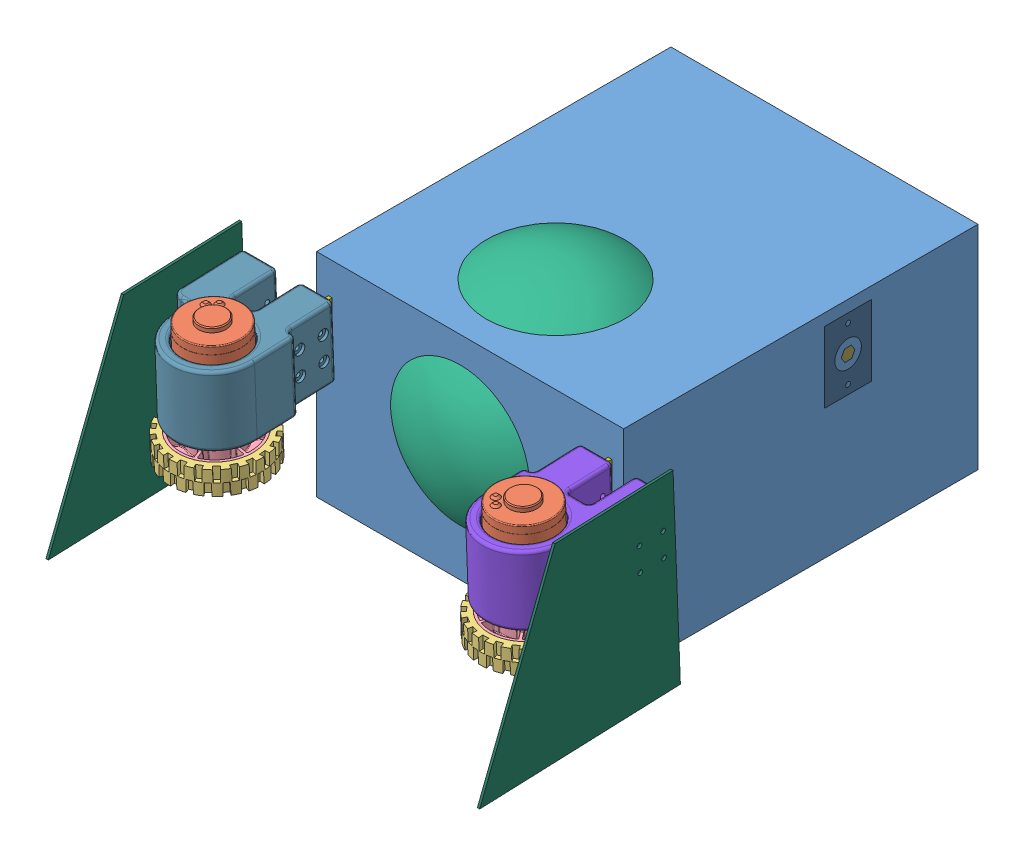
SolidWorks assembly shooter v3, configuration Default. Lengths in mm.
Overall size (466.79 293.17 613.68).
71 component instances, 40 part files, 70 mates.
Components (placement in the parent):
- shooter boundry-1: shooter boundry [Default] at origin size (330.2 228.6 381)
- MiniCIM Motor-1: MiniCIM Motor [Default] at (-2.032 132.5456 487.4581) x (0 0.99925 0.038735) z (0 -0.038735 0.99925) size (133.06 64.01 64.01)
- 4 in HiGrip Wheel-1: 4 in HiGrip Wheel [Default] at (1.2293 109.8239 488.0464) x (0 0.99925 0.038735) z (-0.935788 -0.013657 0.352299) size (35.12 101.6 101.6)
  - 4 in tread-1: 4 in tread [Default] at (-8.0517 2.5236 2.5343) size (25.4 101.6 101.6)
  - 4in 2013 Hub-1: 4in 2013 Hub [Default] at (-8.0517 2.5236 2.5343) size (35.12 82.55 82.55)
- am-0320a_8mm_Key_Hub-1: am-0320a_8mm_Key_Hub [Default] at (-2.032 124.7415 487.1555) x (0.162565 0.03822 -0.985957) z (0 -0.99925 -0.038735) size (57.15 57.15 25.4)
- am-0320a_8mm_Key_Hub-2: am-0320a_8mm_Key_Hub [Default] at (332.232 124.7415 487.1555) x (-0.795747 -0.023459 0.605175) z (0 -0.99925 -0.038735) size (57.15 57.15 25.4)
- 4 in HiGrip Wheel-2: 4 in HiGrip Wheel [Default] at (330.8694 110.0089 483.2753) x (0 0.99925 0.038735) z (0.922364 -0.014964 0.386033) size (35.12 101.6 101.6)
  - 4 in tread-1: 4 in tread [Default] at (-8.0517 2.5236 2.5343) size (25.4 101.6 101.6)
  - 4in 2013 Hub-1: 4in 2013 Hub [Default] at (-8.0517 2.5236 2.5343) size (35.12 82.55 82.55)
- MiniCIM Motor-2: MiniCIM Motor [Default] at (332.232 132.5456 487.4581) x (0 0.99925 0.038735) z (1 0 0) size (133.06 64.01 64.01)
- ball-1: ball [Default] at (154.3361 125.6527 278.3907) x (0.999995 0.002984 0.000631) z (-0.003047 0.986301 0.164927) size (254 254 254)
- shooter bar-1: shooter bar [Default] at (317.5 153.4029 113.3352) x (0 -0.038735 0.99925) z (-1 0 0) size (330.2 50.8 4.06)
- shooter bar-2: shooter bar [Default] at (16.764 153.4029 113.3352) x (0 -0.038735 0.99925) z (-1 0 0) size (330.2 50.8 4.06)
- CIM mount - right - 3d print-2: CIM mount - right - 3d print [Default] at (287.782 124.4786 531.6287) x (1 0 0) z (0 -0.038735 0.99925) size (107.95 76.2 139.7)
- shooter cross bar-3: shooter cross bar [Default] at (16.764 -1.3424 170.8843) x (1 0 0) z (0 -0.038735 0.99925) size (296.67 203.2 50.8)
- shooter cross bar-4: shooter cross bar [Default] at (16.764 -6.2617 297.789) x (1 0 0) z (0 -0.038735 0.99925) size (296.67 203.2 50.8)
- bearing block-1: bearing block [Default] at (330.2 139.7 114.3) x (0 0 1) z (-1 0 0) size (50.8 76.2 8.89)
- bearing block-2: bearing block [Default] at (0 139.7 165.1) x (0 0 -1) z (1 0 0) size (50.8 76.2 8.89)
- .5in hex bearing-3: .5in hex bearing [Default] at (327.66 177.8 139.7) x (0 0.846008 0.53317) z (0 -0.53317 0.846008) size (31.72 7.92 31.72)
- .5in hex bearing-4: .5in hex bearing [Default] at (2.54 177.8 139.7) x (0 -0.846008 -0.53317) z (0 -0.53317 0.846008) size (31.72 7.92 31.72)
- shaft-2: shaft [Default] at (330.2 177.8 139.7) x (0 0.884743 -0.466079) z (-1 0 0) size (14.66 12.7 330.2)
- s35-15he-500h-1: s35-15he-500h [Default] at (283.972 177.8 139.7) x (0 0.038735 -0.99925) z (-1 0 0) size (50.14 50.4 10.29)
- CIM mount - left - 3d print-1: CIM mount - left - 3d print [Default] at (42.418 124.4786 531.6287) x (1 0 0) z (0 -0.038735 0.99925) size (107.95 76.2 139.7)
- gate lifter-1: gate lifter [Default] at (395.732 20.0032 603.8361) x (0 0.038735 -0.99925) z (1 0 0) size (215.9 203.2 2.54)
- gate lifter-2: gate lifter [Default] at (-68.072 20.0032 603.8361) x (0 0.038735 -0.99925) z (1 0 0) size (215.9 203.2 2.54)
- bottom bar-1: bottom bar [Default] at (190.5 -12.2904 348.3935) x (0 0.038735 -0.99925) z (1 0 0) size (304.8 4.06 50.8)
- VEXpro-VersaPlanetary-2stage-with-BAG-1: VEXpro-VersaPlanetary-2stage-with-BAG [Default] at (215.175 156.8 33.7) x (0 0 1) z (-1 0 0) size (49.3 49.3 173.58)
  - 217-2625-001 Rev1-1: 217-2625-001 Rev1 [Default] at origin size (42 42 18)
  - 217-2625-002 Rev1-1: 217-2625-002 Rev1 [Default] at (0 0 -29.4) size (42 42 17.13)
  - 217-2625-003 Rev1-1: 217-2625-003 Rev1 [Default] at (0 0 -43.6478) x (0.966651 -0.256095 0) z (0 0 -1) size (17 17 64.12)
  - 217-2625-009 Rev1-1: 217-2625-009 Rev1 [Default] at (0 0 -3.48) x (-0.609619 0.792694 0) z (0 0 -1) size (18 18 13)
  - 217-2625-100-1: 217-2625-100 [Default] at (0 0 -18.8454) x (0.784104 -0.62063 0) z (0 0 1) size (39.26 38.9 12.7)
    - 217-2625-008 Rev1-1: 217-2625-008 Rev1 [Default] at origin size (34.7 34.7 4.7)
    - 217-2625-010 Rev1-1: 217-2625-010 Rev1 [Default] at (0 10.193 3.65) x (0.999813 0.019336 0) z (0 0 1) size (4 4 12)
    - 217-2625-010 Rev1-2: 217-2625-010 Rev1 [Default] at (8.691 -5.3258 3.65) size (4 4 12)
    - 217-2625-010 Rev1-3: 217-2625-010 Rev1 [Default] at (-8.691 -5.3258 3.65) size (4 4 12)
    - 217-2625-005 Rev1_Planet_Revolving_Follower01-1: 217-2625-005 Rev1_Planet_Revolving_Follower01 [Default] at (8.691 -5.3258 6.35) x (0.932816 0.360354 0) z (0 0 1) size (16.91 16.92 8)
    - 217-2625-005 Rev1_Planet_Revolving_Follower01-2: 217-2625-005 Rev1_Planet_Revolving_Follower01 [Default] at (-8.691 -5.3258 6.35) x (-0.932788 -0.360426 0) z (0 0 1) size (16.91 16.92 8)
    - 217-2625-005 Rev1_Planet_Revolving_Follower01-3: 217-2625-005 Rev1_Planet_Revolving_Follower01 [Default] at (0 10.193 6.35) x (0.893583 0.448898 0) z (0 0 1) size (16.91 16.92 8)
  - 217-2625-007 Rev1_Sun_Driver01-1: 217-2625-007 Rev1_Sun_Driver01 [Default] at (0 0 -11.5575) x (0.564419 -0.825488 0) z (0 0 1) size (14.49 14.49 12.72)
  - 217-2742-1: 217-2742 [Default] at (0 0 -51.4002) x (0 0 1) z (-0.997393 0.072165 0) size (7 28 28)
  - 217-2742-2: 217-2742 [Default] at (0 0 -43.1002) x (0 0 1) z (-1 0 0) size (7 28 28)
  - 217-2741-1: 217-2741 [Default] at (0 0 -7) x (0 0 1) z (-0.951311 0.308231 0) size (5 26 26)
  - TRUARC-MSH-15_98541A410-1: TRUARC-MSH-15_98541A410 [Default] at (0 0 -35.4954) x (0 0 -1) z (0.980859 -0.194721 0) size (1 19.6 17.4)
  - SPRGW0856-1102-012_9714K62-1: SPRGW0856-1102-012_9714K62 [Default] at (0 0 -44.1002) x (-0.695225 0.718792 0) z (-0.718792 -0.695225 0) size (29.09 5.11 30.79)
  - SSS1032-0125ZB_94105A824-1: SSS1032-0125ZB_94105A824 [Default] at (5.4759 4.2112 1.995) x (-0.605001 0.78669 -0.122849) z (0.792694 0.609619 0) size (4.83 4.84 3.3)
  - TRUARC-5103-68_97414A675_grv-1: TRUARC-5103-68_97414A675_grv [Default] at (1.1965 0.0349 -1.3834) x (0 0 -1) z (-0.029125 0.999576 0) size (1.07 15.49 20.19)
  - 217-3351-1: 217-3351 [Default] at (0 0 10.675) x (0 -1 0) z (0 0 -1) size (40.4 40.4 81.5)
  - 217-2816-001 Rev1-1: 217-2816-001 Rev1 [Default] at (0 0 -29.55) x (1 0 0) z (0 0 -1) size (42 42 14.5)
  - SSA_SSA0832-1750ZC-1: SSA_SSA0832-1750ZC [Default] at (-17.5 17.5 -47.261) x (-0.769034 -0.639207 0) z (0.639207 -0.769034 0) size (6.73 48.51 6.73)
  - SSA_SSA0832-1750ZC-2: SSA_SSA0832-1750ZC [Default] at (17.5 -17.5 -47.261) x (0.162252 0.986749 0) z (-0.986749 0.162252 0) size (6.73 48.51 6.73)
  - 217-2625-011 Rev1-1: 217-2625-011 Rev1 [Default] at (0 0 1.37) x (-0.792694 -0.609619 0) z (-0.609619 0.792694 0) size (8.01 7.5 7.94)
  - SSA_SSA0832-0500ZC-1: SSA_SSA0832-0500ZC [Default] at (-17.5 17.5 10.675) x (0.592766 0.805375 0) z (0.805375 -0.592766 0) size (6.73 16.76 6.73)
  - SSA_SSA0832-0500ZC-2: SSA_SSA0832-0500ZC [Default] at (17.5 -17.5 10.675) x (-0.592766 -0.805375 0) z (-0.805375 0.592766 0) size (6.73 16.76 6.73)
  - SSHCM004_SSHCM004070010C-1: SSHCM004_SSHCM004070010C [Default] at (0 -12.5 7.5) x (-0.451598 -0.892221 0) z (0.892221 -0.451598 0) size (7 14 7)
  - SSHCM004_SSHCM004070010C-2: SSHCM004_SSHCM004070010C [Default] at (0 12.5 7.5) x (-0.447517 -0.894275 0) z (0.894275 -0.447517 0) size (7 14 7)
  - 217-2816-001 Rev1-2: 217-2816-001 Rev1 [Default] at (0 0 -16.85) x (1 0 0) z (0 0 -1) size (42 42 14.5)
  - 217-2818 Rev1-1: 217-2818 Rev1 [Default] at (0 0 -31.5454) size (49.07 49.07 17.4)
    - 217-2725-001 Rev1_24t Sun-1: 217-2725-001 Rev1_24t Sun [Default] at (0 0 8.7) size (14.45 14.45 12.7)
    - 217-2725-002 Rev1_24t Planet-1: 217-2725-002 Rev1_24t Planet [Default] at (-12.089 0 6.35) x (-0.130526 0.991445 0) z (0 0 -1) size (13.17 13.15 8)
    - 217-2724-002 Rev1-1: 217-2724-002 Rev1 [Default] x (0.707107 -0.707107 0) z (0 0 -1) size (34.7 34.7 4.7)
    - 217-2625-010 Rev1-1: 217-2625-010 Rev1 [Default] at (-12.089 0 3.65) x (0.971612 -0.236582 0) z (0 0 1) size (4 4 12)
    - 217-2725-002 Rev1_24t Planet-2: 217-2725-002 Rev1_24t Planet [Default] at (0 -12.089 6.35) x (-0.991445 -0.130526 0) z (0 0 -1) size (13.17 13.15 8)
    - 217-2725-002 Rev1_24t Planet-3: 217-2725-002 Rev1_24t Planet [Default] at (12.089 0 6.35) x (0.130526 -0.991445 0) z (0 0 -1) size (13.17 13.15 8)
    - 217-2725-002 Rev1_24t Planet-4: 217-2725-002 Rev1_24t Planet [Default] at (0 12.089 6.35) x (0.991445 0.130526 0) z (0 0 -1) size (13.17 13.15 8)
    - 217-2625-010 Rev1-2: 217-2625-010 Rev1 [Default] at (0 -12.089 3.65) x (0.236582 0.971612 0) z (0 0 1) size (4 4 12)
    - 217-2625-010 Rev1-3: 217-2625-010 Rev1 [Default] at (12.089 0 3.65) x (-0.971612 0.236582 0) z (0 0 1) size (4 4 12)
    - 217-2625-010 Rev1-4: 217-2625-010 Rev1 [Default] at (0 12.089 3.65) x (-0.236582 -0.971612 0) z (0 0 1) size (4 4 12)
  - 217-2822-003 Rev4-1: 217-2822-003 Rev4 [Default] at (0 0 9) x (0 -1 0) z (0 0 1) size (42 42 4.8)
- s35-15he-500h-2: s35-15he-500h [Default] at (283.972 156.8 33.7) x (0 0.721103 -0.692828) z (-1 0 0) size (50.14 50.4 10.29)
Mates (geometry in assembly coordinates):
- Concentric1: concentric aligned: cylinder of 4 in HiGrip Wheel-1/4in 2013 Hub-1 through (-2.032 112.3048 486.6734) axis (0 0.99925 0.038735) radius 14.2875; cylinder of am-0320a_8mm_Key_Hub-1 through (-2.032 99.3605 486.1717) axis (0 0.99925 0.038735) radius 12.1412
- Coincident3: coincident anti-aligned: plane of 4 in HiGrip Wheel-1/4in 2013 Hub-1 through (-2.032 119.2846 486.944) normal (0 0.99925 0.038735); plane of am-0320a_8mm_Key_Hub-1 through (-12.1388 116.9084 548.2422) normal (0 -0.99925 -0.038735)
- Concentric2: concentric anti-aligned: cylinder of 4 in HiGrip Wheel-1/4in 2013 Hub-1 through (-10.4274 85.2489 463.3245) axis (0 0.99925 0.038735) radius 2.159; cylinder of am-0320a_8mm_Key_Hub-1 through (-10.4274 125.6046 464.8888) axis (0 -0.99925 -0.038735) radius 2.5908
- Concentric3: concentric anti-aligned: cylinder of MiniCIM Motor-1 through (-2.032 96.9723 486.0791) axis (0 0.99925 0.038735) radius 4; cylinder of am-0320a_8mm_Key_Hub-1 through (-2.032 124.7415 487.1555) axis (0 -0.99925 -0.038735) radius 4.0259
- Distance1: distance = 3.81 mm anti-aligned: plane of am-0320a_8mm_Key_Hub-1 through (-2.032 124.7415 487.1555) normal (0 0.99925 0.038735); plane of MiniCIM Motor-1 through (-2.032 128.5486 487.3031) normal (0 -0.99925 -0.038735)
- Concentric4: concentric aligned: cylinder of am-0320a_8mm_Key_Hub-2 through (332.232 99.3605 486.1717) axis (0 0.99925 0.038735) radius 12.1412; cylinder of 4 in HiGrip Wheel-2/4in 2013 Hub-1 through (332.232 112.3048 486.6734) axis (0 0.99925 0.038735) radius 14.2875
- Coincident5: coincident anti-aligned: plane of am-0320a_8mm_Key_Hub-2 through (381.7046 120.7431 449.3195) normal (0 -0.99925 -0.038735); plane of 4 in HiGrip Wheel-2/4in 2013 Hub-1 through (332.232 119.2846 486.944) normal (0 0.99925 0.038735)
- Concentric5: concentric anti-aligned: cylinder of am-0320a_8mm_Key_Hub-2 through (308.6112 124.6247 490.1683) axis (0 -0.99925 -0.038735) radius 2.5908; cylinder of 4 in HiGrip Wheel-2/4in 2013 Hub-1 through (308.6112 84.269 488.604) axis (0 0.99925 0.038735) radius 2.159
- Concentric6: concentric anti-aligned: cylinder of am-0320a_8mm_Key_Hub-2 through (332.232 124.7415 487.1555) axis (0 -0.99925 -0.038735) radius 4.0259; cylinder of MiniCIM Motor-2 through (332.232 96.9723 486.0791) axis (0 0.99925 0.038735) radius 4
- Distance2: distance = 3.81 mm anti-aligned: plane of am-0320a_8mm_Key_Hub-2 through (332.232 124.7415 487.1555) normal (0 0.99925 0.038735); plane of MiniCIM Motor-2 through (332.232 128.5486 487.3031) normal (0 -0.99925 -0.038735)
- Coincident7: coincident aligned: plane of MiniCIM Motor-1 through (-2.032 132.5456 487.4581) normal (0 -0.99925 -0.038735); plane of MiniCIM Motor-2 through (332.232 132.5456 487.4581) normal (0 -0.99925 -0.038735)
- Distance5: distance = 304.8 mm anti-aligned: plane of shooter bar-1 through (317.5 153.4029 113.3352) normal (1 0 0); plane of shooter bar-2 through (12.7 153.4029 113.3352) normal (-1 0 0)
- Width1: width anti-aligned: plane of shooter boundry-1 through (0 0 381) normal (-1 0 0); plane of shooter boundry-1 through (330.2 0 381) normal (1 0 0); plane of shooter bar-1 through (317.5 153.4029 113.3352) normal (1 0 0); plane of shooter bar-2 through (12.7 153.4029 113.3352) normal (-1 0 0)
- Concentric24: concentric aligned: cylinder of MiniCIM Motor-2 through (332.232 140.769 487.7768) axis (0 0.99925 0.038735) radius 32.004; cylinder of CIM mount - right - 3d print-2 through (332.232 32.8758 483.5944) axis (0 0.99925 0.038735) radius 33.02
- Concentric25: concentric anti-aligned: cylinder of MiniCIM Motor-2 through (332.232 133.5295 462.0771) axis (0 -0.99925 -0.038735) radius 2.0193; cylinder of CIM mount - right - 3d print-2 through (332.232 133.5295 462.0771) axis (0 0.99925 0.038735) radius 2.5527
- Coincident23: coincident anti-aligned: plane of MiniCIM Motor-2 through (332.232 132.5456 487.4581) normal (0 -0.99925 -0.038735); plane of CIM mount - right - 3d print-2 through (287.782 130.8238 531.8747) normal (0 0.99925 0.038735)
- Concentric28: concentric anti-aligned: cylinder of shooter bar-2 through (12.7 188.5227 190.9538) axis (-1 0 0) radius 2.5527; cylinder of shooter cross bar-3 through (20.828 188.5227 190.9538) axis (1 0 0) radius 2.5527
- Concentric29: concentric anti-aligned: cylinder of shooter bar-2 through (12.7 162.1579 215.3509) axis (-1 0 0) radius 2.5527; cylinder of shooter cross bar-3 through (20.828 162.1579 215.3509) axis (1 0 0) radius 2.5527
- Coincident25: coincident anti-aligned: plane of shooter bar-2 through (16.764 153.4029 113.3352) normal (1 0 0); plane of shooter cross bar-3 through (16.764 199.7374 229.5172) normal (-1 0 0)
- Concentric30: concentric aligned: cylinder of shooter bar-1 through (313.436 188.5227 190.9538) axis (-1 0 0) radius 2.5527; cylinder of shooter cross bar-3 through (309.372 188.5227 190.9538) axis (-1 0 0) radius 2.5527
- Concentric31: concentric anti-aligned: cylinder of shooter bar-2 through (12.7 157.2386 342.2556) axis (-1 0 0) radius 2.5527; cylinder of shooter cross bar-4 through (20.828 157.2386 342.2556) axis (1 0 0) radius 2.5527
- Concentric32: concentric anti-aligned: cylinder of shooter bar-2 through (12.7 183.6034 317.8585) axis (-1 0 0) radius 2.5527; cylinder of shooter cross bar-4 through (20.828 183.6034 317.8585) axis (1 0 0) radius 2.5527
- Coincident26: coincident anti-aligned: plane of shooter bar-2 through (16.764 153.4029 113.3352) normal (1 0 0); plane of shooter cross bar-4 through (16.764 194.818 356.4218) normal (-1 0 0)
- Tangent6: tangent anti-aligned: sphere of ball-1; plane of shooter cross bar-4 through (107.3474 -4.1685 348.7083) normal (0 0.99925 0.038735)
- Coincident32: coincident aligned: plane of shooter boundry-1 through (330.2 0 381) normal (1 0 0); plane of bearing block-1 through (330.2 139.7 114.3) normal (1 0 0)
- Distance7: distance = 12.7 mm aligned: plane of bearing block-1 through (321.31 215.9 114.3) normal (0 1 0); plane of shooter boundry-1 through (0 228.6 381) normal (0 1 0)
- Distance8: distance = 114.3 mm aligned: plane of bearing block-1 through (321.31 139.7 114.3) normal (0 0 -1); plane of shooter boundry-1 through (0 0 0) normal (0 0 -1)
- Coincident36: coincident anti-aligned: plane of shooter bar-1 through (317.5 153.4029 113.3352) normal (1 0 0); plane of CIM mount - right - 3d print-2 through (317.5 194.6113 394.5424) normal (-1 0 0)
- Coincident39: coincident anti-aligned: plane of bearing block-1 through (321.31 139.7 114.3) normal (-1 0 0); plane of .5in hex bearing-3 through (321.31 177.8 139.7) normal (1 0 0)
- Concentric34: concentric aligned: cylinder of bearing block-1 through (321.31 177.8 139.7) axis (1 0 0) radius 14.2875; cylinder of .5in hex bearing-3 through (319.7352 177.8 139.7) axis (1 0 0) radius 14.2875
- Coincident46: coincident aligned: plane of bearing block-1 through (330.2 139.7 114.3) normal (1 0 0); plane of shaft-2 through (330.2 177.8 139.7) normal (1 0 0)
- Coincident47: coincident anti-aligned: plane of .5in hex bearing-3 through (319.7352 178.084 132.3732) normal (0 0.466079 0.884743); plane of shaft-2 through (0 178.084 132.3732) normal (0 -0.466079 -0.884743)
- Coincident48: coincident anti-aligned: plane of .5in hex bearing-4 through (10.4648 171.5968 135.7906) normal (0 0.466079 0.884743); plane of shaft-2 through (0 178.084 132.3732) normal (0 -0.466079 -0.884743)
- Coincident49: coincident anti-aligned: plane of .5in hex bearing-4 through (10.4648 171.3128 143.1175) normal (0 0.99925 0.038735); plane of shaft-2 through (0 171.5968 135.7906) normal (0 -0.99925 -0.038735)
- Coincident53: coincident anti-aligned: plane of shooter bar-1 through (317.5 171.5968 135.7906) normal (0 0.99925 0.038735); plane of shaft-2 through (0 171.5968 135.7906) normal (0 -0.99925 -0.038735)
- Coincident54: coincident anti-aligned: plane of shooter bar-2 through (16.764 171.5968 135.7906) normal (0 0.99925 0.038735); plane of shaft-2 through (0 171.5968 135.7906) normal (0 -0.99925 -0.038735)
- Coincident55: coincident anti-aligned: plane of shooter bar-2 through (16.764 171.3128 143.1175) normal (0 0.53317 -0.846008); plane of shaft-2 through (0 171.3128 143.1175) normal (0 -0.53317 0.846008)
- Coincident59: coincident aligned: plane of shooter boundry-1 through (0 0 381) normal (-1 0 0); plane of bearing block-2 through (0 139.7 165.1) normal (-1 0 0)
- Coincident60: coincident aligned: plane of bearing block-1 through (321.31 215.9 114.3) normal (0 1 0); plane of bearing block-2 through (8.89 215.9 165.1) normal (0 1 0)
- Coincident61: coincident anti-aligned: plane of bearing block-2 through (8.89 139.7 165.1) normal (1 0 0); plane of .5in hex bearing-4 through (8.89 177.8 139.7) normal (-1 0 0)
- Concentric35: concentric aligned: cylinder of bearing block-2 through (8.89 177.8 139.7) axis (-1 0 0) radius 14.2875; cylinder of .5in hex bearing-4 through (10.4648 177.8 139.7) axis (-1 0 0) radius 14.2875
- Coincident65: coincident anti-aligned: plane of shaft-2 through (0 184.0032 143.6094) normal (0 0.99925 0.038735); plane of s35-15he-500h-1 through (288.036 184.0032 143.6094) normal (0 -0.99925 -0.038735)
- Coincident66: coincident anti-aligned: plane of shaft-2 through (0 184.2872 136.2825) normal (0 0.53317 -0.846008); plane of s35-15he-500h-1 through (288.036 180.1058 133.6473) normal (0 -0.53317 0.846008)
- Distance10: distance = 25.4 mm anti-aligned: plane of s35-15he-500h-1 through (288.036 177.8 139.7) normal (1 0 0); plane of shooter bar-1 through (313.436 153.4029 113.3352) normal (-1 0 0)
- Coincident68: coincident anti-aligned: plane of shooter bar-1 through (317.5 153.4029 113.3352) normal (1 0 0); plane of CIM mount - right - 3d print-2 through (317.5 194.6113 394.5424) normal (-1 0 0)
- Concentric36: concentric aligned: cylinder of shooter bar-1 through (313.436 154.7789 405.7079) axis (-1 0 0) radius 2.5527; cylinder of CIM mount - right - 3d print-2 through (297.307 154.7789 405.7079) axis (-1 0 0) radius 2.5527
- Concentric37: concentric aligned: cylinder of shooter bar-1 through (313.436 179.176 432.0727) axis (-1 0 0) radius 2.5527; cylinder of CIM mount - right - 3d print-2 through (297.307 179.176 432.0727) axis (-1 0 0) radius 2.5527
- Concentric38: concentric anti-aligned: cylinder of MiniCIM Motor-1 through (-27.432 132.5456 487.4581) axis (0 -0.99925 -0.038735) radius 2.0193; cylinder of CIM mount - left - 3d print-1 through (-27.432 132.5456 487.4581) axis (0 0.99925 0.038735) radius 2.5527
- Concentric39: concentric aligned: cylinder of MiniCIM Motor-1 through (-2.032 140.769 487.7768) axis (0 0.99925 0.038735) radius 32.004; cylinder of CIM mount - left - 3d print-1 through (-2.032 32.8758 483.5944) axis (0 0.99925 0.038735) radius 33.02
- Coincident69: coincident anti-aligned: plane of shooter bar-2 through (12.7 153.4029 113.3352) normal (-1 0 0); plane of CIM mount - left - 3d print-1 through (12.7 194.6113 394.5424) normal (1 0 0)
- Concentric40: concentric anti-aligned: cylinder of shooter bar-2 through (12.7 180.1598 406.6918) axis (-1 0 0) radius 2.5527; cylinder of CIM mount - left - 3d print-1 through (32.893 180.1598 406.6918) axis (1 0 0) radius 2.5527
- Concentric41: concentric anti-aligned: cylinder of shooter bar-2 through (12.7 153.795 431.0888) axis (-1 0 0) radius 2.5527; cylinder of CIM mount - left - 3d print-1 through (32.893 153.795 431.0888) axis (1 0 0) radius 2.5527
- Coincident71: coincident anti-aligned: plane of CIM mount - right - 3d print-2 through (395.732 124.4786 531.6287) normal (1 0 0); plane of gate lifter-1 through (395.732 20.0032 603.8361) normal (-1 0 0)
- Concentric42: concentric aligned: cylinder of CIM mount - right - 3d print-2 through (395.732 180.1598 406.6918) axis (1 0 0) radius 2.5527; cylinder of gate lifter-1 through (398.272 180.1598 406.6918) axis (1 0 0) radius 2.5527
- Concentric43: concentric aligned: cylinder of CIM mount - right - 3d print-2 through (395.732 153.795 431.0888) axis (1 0 0) radius 2.5527; cylinder of gate lifter-1 through (398.272 153.795 431.0888) axis (1 0 0) radius 2.5527
- Coincident72: coincident anti-aligned: plane of CIM mount - left - 3d print-1 through (-65.532 124.4786 531.6287) normal (-1 0 0); plane of gate lifter-2 through (-65.532 20.0032 603.8361) normal (1 0 0)
- Concentric44: concentric anti-aligned: cylinder of CIM mount - left - 3d print-1 through (-65.532 180.1598 406.6918) axis (-1 0 0) radius 2.5527; cylinder of gate lifter-2 through (-65.532 180.1598 406.6918) axis (1 0 0) radius 2.5527
- Concentric45: concentric anti-aligned: cylinder of CIM mount - left - 3d print-1 through (-65.532 153.795 431.0888) axis (-1 0 0) radius 2.5527; cylinder of gate lifter-2 through (-65.532 153.795 431.0888) axis (1 0 0) radius 2.5527
- Coincident74: coincident anti-aligned: plane of shooter cross bar-4 through (105.664 -8.2295 348.5509) normal (0 -0.99925 -0.038735); plane of bottom bar-1 through (190.5 -8.2295 348.5509) normal (0 0.99925 0.038735)
- Coincident75: coincident aligned: plane of shooter cross bar-4 through (16.764 -8.2295 348.5509) normal (0 -0.038735 0.99925); plane of bottom bar-1 through (190.5 -8.2295 348.5509) normal (0 -0.038735 0.99925)
- Concentric46: concentric aligned: cylinder of shooter cross bar-4 through (152.4 -2.6927 310.6369) axis (0 0.99925 0.038735) radius 1.5875; cylinder of bottom bar-1 through (152.4 -6.7537 310.4795) axis (0 0.99925 0.038735) radius 1.5875
- Concentric47: concentric aligned: cylinder of shooter cross bar-4 through (177.8 -3.6766 336.0178) axis (0 0.99925 0.038735) radius 1.5875; cylinder of bottom bar-1 through (177.8 -7.7375 335.8604) axis (0 0.99925 0.038735) radius 1.5875
- Concentric48: concentric aligned: cylinder of shooter cross bar-3 through (177.8 2.2266 183.7322) axis (0 0.99925 0.038735) radius 1.5875; cylinder of bottom bar-1 through (177.8 -1.8343 183.5748) axis (0 0.99925 0.038735) radius 1.5875
- Concentric49: concentric aligned: cylinder of shooter cross bar-3 through (152.4 1.2428 209.1131) axis (0 0.99925 0.038735) radius 1.5875; cylinder of bottom bar-1 through (152.4 -2.8182 208.9557) axis (0 0.99925 0.038735) radius 1.5875
- Distance13: distance = 12.7 mm aligned: plane of shooter boundry-1 through (0 0 0) normal (0 0 -1); plane of VEXpro-VersaPlanetary-2stage-with-BAG-1/217-2625-002 Rev1-1 through (266.7 135.8 12.7) normal (0 0 -1)
- Distance11: distance = 50.8 mm aligned: plane of VEXpro-VersaPlanetary-2stage-with-BAG-1/217-2625-001 Rev1-1 through (219.175 177.8 12.7) normal (0 1 0); plane of shooter boundry-1 through (0 228.6 381) normal (0 1 0)
- Distance12: distance = 63.5 mm aligned: plane of VEXpro-VersaPlanetary-2stage-with-BAG-1/217-2625-002 Rev1-1 through (266.7 177.8 12.7) normal (1 0 0); plane of shooter boundry-1 through (330.2 0 381) normal (1 0 0)
- Coincident80: coincident aligned: plane of s35-15he-500h-1 through (288.036 177.8 139.7) normal (1 0 0); plane of s35-15he-500h-2 through (288.036 156.8 33.7) normal (1 0 0)
- GearMate1: gear = 5.1816 : 5.1816 mm: cylinder of s35-15he-500h-2 through (288.036 179.4914 30.5697) axis (1 0 0) radius 2.5908; cylinder of s35-15he-500h-1 through (288.036 198.0662 129.0238) axis (1 0 0) radius 2.5908
- Concentric50: concentric anti-aligned: cylinder of VEXpro-VersaPlanetary-2stage-with-BAG-1/217-2625-003 Rev1-1 through (308.5752 156.8 33.7) axis (1 0 0) radius 2.5527; cylinder of s35-15he-500h-2 through (280.289 156.8 33.7) axis (-1 0 0) radius 12.7
